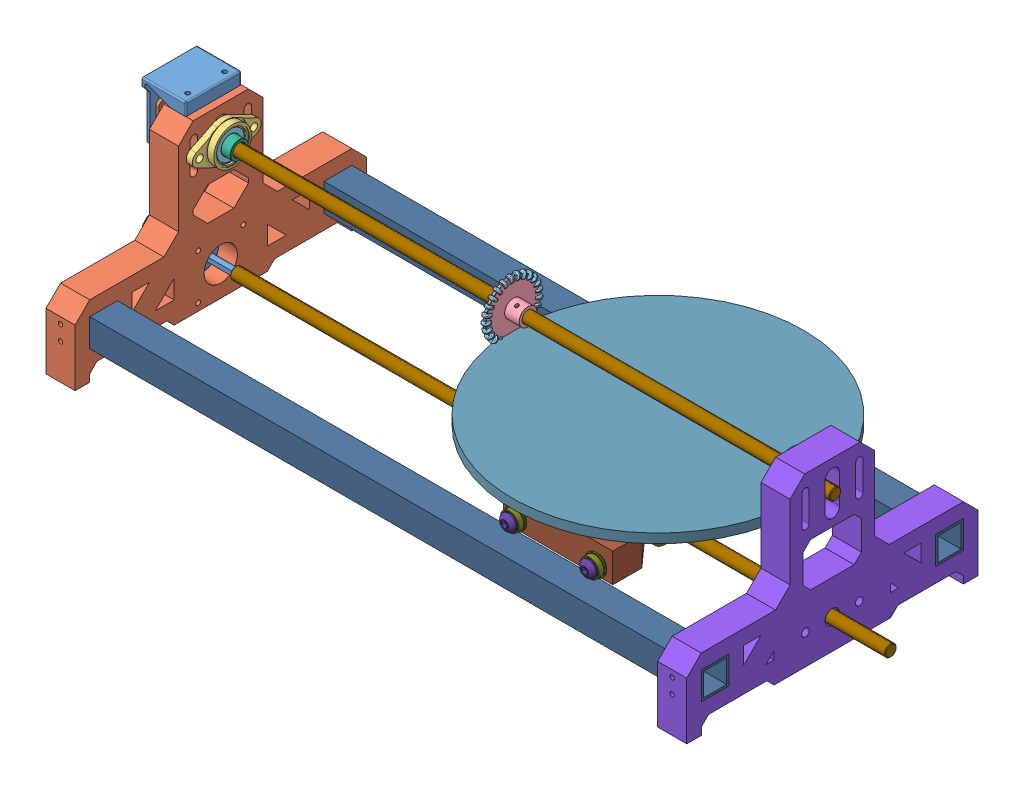
SolidWorks assembly Integrator, configuration Default. Lengths in mm.
Overall size (495.22 128.35 224.42).
89 component instances, 23 part files, 44 mates.
Components (placement in the parent):
- NEMA_17_PHB42S20-410-TB-1: NEMA_17_PHB42S20-410-TB [Default] at (1086 20.8 -85) x (0 -1 0) z (-1 0 0) size (42.3 42.3 43.3)
- Motor Side-1: Motor Side [Default] at (0 0 -100) size (20 120 200)
- Zinc Alloy Pillow Block Flange Bearing KFL08 ID-8mm-1: Zinc Alloy Pillow Block Flange Bearing KFL08 ID-8mm [Default] at (20 99.525 -100) x (0 0 -1) z (1 0 0) size (47.3 26.5 12.88)
  - Zinc Alloy Pillow Block Flange Bearing KFL08 ID-8mm.stp-1: Zinc Alloy Pillow Block Flange Bearing KFL08 ID-8mm.stp [Default] at origin size (47.3 26.5 12.88)
    - Flange.stp-1: Flange.stp [Default] x (-1 0 0) z (0 0 1) size (47.3 26.5 8.16)
    - Bearing 61801-2Z GB_T 276-94.stp-1: Bearing 61801-2Z GB_T 276-94.stp [Default] at (0 0 1.525) x (0 0 1) z (-0.985741 0.16827 0) size (5 21 21)
    - DIN 988 - 13 x 19 x 1.stp-1: DIN 988 - 13 x 19 x 1.stp [Default] at (0 0 5.6917) x (-0.369618 -0.929184 0) z (0 0 1) size (19 19 1)
    - DIN 988 - 13 x 19 x 1.stp-2: DIN 988 - 13 x 19 x 1.stp [Default] at (0 0 1.3583) x (0.999993 0.003767 0) z (0 0 1) size (19 19 1)
    - Collar 8x12.35x11.35.stp-1: Collar 8x12.35x11.35.stp [Default] at (0 0 1.525) x (0.825043 -0.56507 0) z (-0.56507 -0.825043 0) size (12.36 11.35 12.36)
    - IS_ 6094 - M3 x 2(1).stp-1: IS_ 6094 - M3 x 2(1).stp [Default] at (3.7491 -1.3208 9.875) x (0.943181 -0.332278 0) z (0 0 1) size (2 3 3)
    - IS_ 6094 - M3 x 2(1).stp-2: IS_ 6094 - M3 x 2(1).stp [Default] at (-2.2462 -3.2795 9.875) x (-0.56507 -0.825043 0) z (0 0 1) size (2 3 3)
    - IS_ 6094 - M3 x 2(1).stp-3: IS_ 6094 - M3 x 2(1).stp [Default] at (3.7491 -1.3208 9.875) x (0.943181 -0.332278 0) z (0 0 1) size (2 3 3)
- Non-motor Side -1: Non-motor Side  [Default] at (440 0 -100) x (-1 0 0) z (0 0 -1) size (20 120 200)
- Zinc Alloy Pillow Block Flange Bearing KFL08 ID-8mm-2: Zinc Alloy Pillow Block Flange Bearing KFL08 ID-8mm [Default] at (430 25.5 -100) x (0 0 1) z (-1 0 0) size (47.3 26.5 12.88)
  - Zinc Alloy Pillow Block Flange Bearing KFL08 ID-8mm.stp-1: Zinc Alloy Pillow Block Flange Bearing KFL08 ID-8mm.stp [Default] at origin size (47.3 26.5 12.88)
    - Flange.stp-1: Flange.stp [Default] x (-1 0 0) z (0 0 1) size (47.3 26.5 8.16)
    - Bearing 61801-2Z GB_T 276-94.stp-1: Bearing 61801-2Z GB_T 276-94.stp [Default] at (0 0 1.525) x (0 0 1) z (-0.985741 0.16827 0) size (5 21 21)
    - DIN 988 - 13 x 19 x 1.stp-1: DIN 988 - 13 x 19 x 1.stp [Default] at (0 0 5.6917) x (-0.369618 -0.929184 0) z (0 0 1) size (19 19 1)
    - DIN 988 - 13 x 19 x 1.stp-2: DIN 988 - 13 x 19 x 1.stp [Default] at (0 0 1.3583) x (0.999993 0.003767 0) z (0 0 1) size (19 19 1)
    - Collar 8x12.35x11.35.stp-1: Collar 8x12.35x11.35.stp [Default] at (0 0 1.525) x (0.825043 -0.56507 0) z (-0.56507 -0.825043 0) size (12.36 11.35 12.36)
    - IS_ 6094 - M3 x 2(1).stp-1: IS_ 6094 - M3 x 2(1).stp [Default] at (3.7491 -1.3208 9.875) x (0.943181 -0.332278 0) z (0 0 1) size (2 3 3)
    - IS_ 6094 - M3 x 2(1).stp-2: IS_ 6094 - M3 x 2(1).stp [Default] at (-2.2462 -3.2795 9.875) x (-0.56507 -0.825043 0) z (0 0 1) size (2 3 3)
    - IS_ 6094 - M3 x 2(1).stp-3: IS_ 6094 - M3 x 2(1).stp [Default] at (3.7491 -1.3208 9.875) x (0.943181 -0.332278 0) z (0 0 1) size (2 3 3)
- Zinc Alloy Pillow Block Flange Bearing KFL08 ID-8mm-3: Zinc Alloy Pillow Block Flange Bearing KFL08 ID-8mm [Default] at (420 99.525 -100) x (0 0 1) z (-1 0 0) size (47.3 26.5 12.88)
  - Zinc Alloy Pillow Block Flange Bearing KFL08 ID-8mm.stp-1: Zinc Alloy Pillow Block Flange Bearing KFL08 ID-8mm.stp [Default] at origin size (47.3 26.5 12.88)
    - Flange.stp-1: Flange.stp [Default] x (-1 0 0) z (0 0 1) size (47.3 26.5 8.16)
    - Bearing 61801-2Z GB_T 276-94.stp-1: Bearing 61801-2Z GB_T 276-94.stp [Default] at (0 0 1.525) x (0 0 1) z (-0.985741 0.16827 0) size (5 21 21)
    - DIN 988 - 13 x 19 x 1.stp-1: DIN 988 - 13 x 19 x 1.stp [Default] at (0 0 5.6917) x (-0.369618 -0.929184 0) z (0 0 1) size (19 19 1)
    - DIN 988 - 13 x 19 x 1.stp-2: DIN 988 - 13 x 19 x 1.stp [Default] at (0 0 1.3583) x (0.999993 0.003767 0) z (0 0 1) size (19 19 1)
    - Collar 8x12.35x11.35.stp-1: Collar 8x12.35x11.35.stp [Default] at (0 0 1.525) x (0.825043 -0.56507 0) z (-0.56507 -0.825043 0) size (12.36 11.35 12.36)
    - IS_ 6094 - M3 x 2(1).stp-1: IS_ 6094 - M3 x 2(1).stp [Default] at (3.7491 -1.3208 9.875) x (0.943181 -0.332278 0) z (0 0 1) size (2 3 3)
    - IS_ 6094 - M3 x 2(1).stp-2: IS_ 6094 - M3 x 2(1).stp [Default] at (-2.2462 -3.2795 9.875) x (-0.56507 -0.825043 0) z (0 0 1) size (2 3 3)
    - IS_ 6094 - M3 x 2(1).stp-3: IS_ 6094 - M3 x 2(1).stp [Default] at (3.7491 -1.3208 9.875) x (0.943181 -0.332278 0) z (0 0 1) size (2 3 3)
- 8mmby450mm-1: 8mmby450mm [Default] at (-7.888 99.525 -100) x (1 0 0) z (0 -0.729222 0.684277) size (450 8 8)
- .75inby440mm-1: .75inby440mm [Default] at (0 29.525 -180.475) size (440 19.05 19.05)
- .75inby440mm-2: .75inby440mm [Default] at (0 29.525 -19.525) size (440 19.05 19.05)
- 8mmby450mm-2: 8mmby450mm [Default] at (30.3 25.5 -100) x (1 0 0) z (0 0.801211 0.598382) size (450 8 8)
- Cart-1: Cart [Default] at (362.9308 -35.5181 5.9339) x (-1 0 0) z (0 0 -1) size (224.42 72.46 224.42)
  - Cart_base-1: Cart_base [Default] at (5.4308 73.0181 37.6181) size (75 44 139.54)
  - NEMA_17_PHB42S20-410-TB-1: NEMA_17_PHB42S20-410-TB [Default] at (27.9308 1160.0181 151.3181) x (0 0 1) z (0 -1 0) size (42.3 42.3 43.3)
  - Gear-1: Gear [Default] at (42.9308 107.2581 146.6181) x (-0.116014 0 -0.993248) z (0 -1 0) size (44.15 44.15 25.24)
  - Gear - Copy-4: Gear - Copy [Default] at (42.9308 97.2581 106.1181) x (-0.799247 0 0.601003) z (0 1 0) size (44.15 44.15 13.5)
  - Disc-1: Disc [Default] at (42.9308 121.4821 106.1181) x (0.13069 0 0.991423) z (0.991423 0 -0.13069) size (200 6.35 200)
  - socket countersunk head screw_am-1: socket countersunk head screw_am [B18.3.5M - 3 x 0.5 x 30 Socket FCHS  -- 30N] at (58.4308 93.7781 162.1181) x (0 -1 0) z (-0.022228 0 0.999753) size (30 5.35 5.35)
  - socket countersunk head screw_am-2: socket countersunk head screw_am [B18.3.5M - 3 x 0.5 x 30 Socket FCHS  -- 30N] at (58.4308 93.7781 131.1181) x (0 -1 0) z (-0.024735 0 0.999694) size (30 5.35 5.35)
  - socket countersunk head screw_am-3: socket countersunk head screw_am [B18.3.5M - 3 x 0.5 x 30 Socket FCHS  -- 30N] at (27.4308 93.7781 162.1181) x (0 -1 0) z (0.002833 0 0.999996) size (30 5.35 5.35)
  - socket countersunk head screw_am-4: socket countersunk head screw_am [B18.3.5M - 3 x 0.5 x 30 Socket FCHS  -- 30N] at (27.4308 93.7781 131.1181) x (0 -1 0) z (0.022473 0 0.999747) size (30 5.35 5.35)
  - Flanged_0.25x0.5-1: Flanged_0.25x0.5 [Default] at (70.4308 80.8921 36.3481) x (0.805459 0.592651 0) z (-0.592651 0.805459 0) size (14.29 4.76 14.29)
  - Flanged_0.25x0.5-2: Flanged_0.25x0.5 [Default] at (70.4308 80.8921 175.8881) x (0.805459 0.592651 0) z (0.592651 -0.805459 0) size (14.29 4.76 14.29)
  - Flanged_0.25x0.5-3: Flanged_0.25x0.5 [Default] at (15.4308 80.8921 36.3481) x (0.998389 0.056737 0) z (-0.056737 0.998389 0) size (14.29 4.76 14.29)
  - Flanged_0.25x0.5-4: Flanged_0.25x0.5 [Default] at (15.4308 80.8921 175.8881) x (0.998389 0.056737 0) z (0.056737 -0.998389 0) size (14.29 4.76 14.29)
  - Flanged_0.25x0.5-5: Flanged_0.25x0.5 [Default] at (42.9308 96.0516 106.1181) size (14.29 4.76 14.29)
  - Flanged_0.25x0.5-6: Flanged_0.25x0.5 [Default] at (42.9308 108.4646 106.1181) x (-0.194861 0 -0.980831) z (-0.980831 0 0.194861) size (14.29 4.76 14.29)
  - socket button head cap screw_ai-2: socket button head cap screw_ai [SBHCSCREW 0.19-32x0.25-HX-N] at (42.9308 111.03 106.1181) x (0 -1 0) z (0 0 1) size (8.92 9.17 9.17)
  - socket button head cap screw_ai-4: socket button head cap screw_ai [SBHCSCREW 0.25-20x0.25-HX-N] at (70.4308 80.8921 184.0034) x (0 0 -1) z (1 0 0) size (9.7 11.1 11.1)
  - socket button head cap screw_ai-5: socket button head cap screw_ai [SBHCSCREW 0.25-20x0.25-HX-N] at (15.4308 80.8921 184.0034) x (0 0 -1) z (1 0 0) size (9.7 11.1 11.1)
  - socket button head cap screw_ai-6: socket button head cap screw_ai [SBHCSCREW 0.25-20x0.25-HX-N] at (70.4308 80.8921 28.2328) x (0 0 1) z (-1 0 0) size (9.7 11.1 11.1)
  - socket button head cap screw_ai-7: socket button head cap screw_ai [SBHCSCREW 0.25-20x0.25-HX-N] at (15.4308 80.8921 28.2328) x (0 0 1) z (-1 0 0) size (9.7 11.1 11.1)
  - Disc_adapter-1: Disc_adapter [Default] at (42.9308 107.2581 106.1181) size (30.05 10.92 30.05)
- Encoder_mount_VER2-1: Encoder_mount_VER2 [Default] at (-14.92 88.35 -100) x (0 0 -1) z (1 0 0) size (38.1 40 30)
- AS5600 Magntic encoder-1: AS5600 Magntic encoder [Default] at (-12.92 100.7427 -100.0029) x (0 0 -1) z (1 0 0) size (23.2 22.7 2)
- Magnet Holder-1: Magnet Holder [Default] at (-0.92 99.525 -100) x (0 -0.824688 0.565588) z (0 -0.565588 -0.824688) size (12 10 12)
- Follower_wheel-1: Follower_wheel [Default] at (220 99.525 -100) x (1 0 0) z (0 -0.438791 0.898589) size (14.36 42.16 42.24)
  - Follower Wheel-1: Follower Wheel [Default] at origin size (12 37.52 37.56)
  - bead-1: bead [Default] at (0 17.6007 2.2235) x (0 0.125333 -0.992115) z (0.45035 0.885812 0.111904) size (2 5 5)
  - bead-2: bead [Default] at (0 16.4948 6.5307) x (0 0.368125 -0.929776) z (0.45035 0.830153 0.328681) size (2 5 5)
  - bead-3: bead [Default] at (0 14.3524 10.4276) x (0 0.587785 -0.809017) z (0.45035 0.722333 0.524805) size (2 5 5)
  - bead-4: bead [Default] at (0 11.3083 13.6693) x (0 0.770513 -0.637424) z (0.45035 0.569125 0.687954) size (2 5 5)
  - bead-5: bead [Default] at (0 7.5536 16.0521) x (0 0.904827 -0.425779) z (0.45035 0.380158 0.807877) size (2 5 5)
  - bead-6: bead [Default] at (0 3.3243 17.4263) x (0 0.982287 -0.187381) z (0.45035 0.167304 0.877037) size (2 5 5)
  - bead-7: bead [Default] at (0 -1.1139 17.7056) x (0 0.998027 0.062791) z (0.45035 -0.056063 0.89109) size (2 5 5)
  - bead-8: bead [Default] at (0 -5.4821 16.8723) x (0 0.951057 0.309017) z (0.45035 -0.275907 0.849153) size (2 5 5)
  - bead-9: bead [Default] at (0 -9.5059 14.9789) x (0 0.844328 0.535827) z (0.45035 -0.478414 0.75386) size (2 5 5)
  - bead-10: bead [Default] at (0 -12.9323 12.1443) x (0 0.684547 0.728969) z (0.45035 -0.650861 0.611199) size (2 5 5)
  - bead-11: bead [Default] at (0 -15.5462 8.5466) x (0 0.481754 0.876307) z (0.45035 -0.782412 0.430135) size (2 5 5)
  - bead-12: bead [Default] at (0 -17.1832 4.4119) x (0 0.24869 0.968583) z (0.45035 -0.864802 0.222043) size (2 5 5)
  - bead-13: bead [Default] at (0 -17.7406 0) x (0 0 1) z (0.45035 -0.892852 0) size (2 5 5)
  - bead-14: bead [Default] at (0 -17.1832 -4.4119) x (0 -0.24869 0.968583) z (0.45035 -0.864802 -0.222043) size (2 5 5)
  - bead-15: bead [Default] at (0 -15.5462 -8.5466) x (0 -0.481754 0.876307) z (0.45035 -0.782412 -0.430135) size (2 5 5)
  - bead-16: bead [Default] at (0 -12.9323 -12.1443) x (0 -0.684547 0.728969) z (0.45035 -0.650861 -0.611199) size (2 5 5)
  - bead-17: bead [Default] at (0 -9.5059 -14.9789) x (0 -0.844328 0.535827) z (0.45035 -0.478414 -0.75386) size (2 5 5)
  - bead-18: bead [Default] at (0 -5.4821 -16.8723) x (0 -0.951057 0.309017) z (0.45035 -0.275907 -0.849153) size (2 5 5)
  - bead-19: bead [Default] at (0 -1.1139 -17.7056) x (0 -0.998027 0.062791) z (0.45035 -0.056063 -0.89109) size (2 5 5)
  - bead-20: bead [Default] at (0 3.3243 -17.4263) x (0 -0.982287 -0.187381) z (0.45035 0.167304 -0.877037) size (2 5 5)
  - bead-21: bead [Default] at (0 7.5536 -16.0521) x (0 -0.904827 -0.425779) z (0.45035 0.380158 -0.807877) size (2 5 5)
  - bead-22: bead [Default] at (0 11.3083 -13.6693) x (0 -0.770513 -0.637424) z (0.45035 0.569125 -0.687954) size (2 5 5)
  - bead-23: bead [Default] at (0 14.3524 -10.4276) x (0 -0.587785 -0.809017) z (0.45035 0.722333 -0.524805) size (2 5 5)
  - bead-24: bead [Default] at (0 16.4948 -6.5307) x (0 -0.368125 -0.929776) z (0.45035 0.830153 -0.328681) size (2 5 5)
  - bead-25: bead [Default] at (0 17.6007 -2.2235) x (0 -0.125333 -0.992115) z (0.45035 0.885812 -0.111904) size (2 5 5)
Mates (geometry in assembly coordinates):
- Coincident3: coincident anti-aligned: plane of NEMA_17_PHB42S20-410-TB-1 through (6 25.5 -100) normal (1 0 0); plane of Motor Side-1 through (6 0 -100) normal (-1 0 0)
- Concentric3: concentric anti-aligned: cylinder of NEMA_17_PHB42S20-410-TB-1 through (8 25.5 -100) axis (-1 0 0) radius 11; cylinder of Motor Side-1 through (0 25.5 -100) axis (1 0 0) radius 11.5
- Concentric4: concentric anti-aligned: cylinder of NEMA_17_PHB42S20-410-TB-1 through (19 41 -84.5) axis (-1 0 0) radius 1.25; cylinder of Motor Side-1 through (0 41 -84.5) axis (1 0 0) radius 1.6
- Coincident4: coincident anti-aligned: plane of Motor Side-1 through (20 0 -100) normal (1 0 0); plane of Zinc Alloy Pillow Block Flange Bearing KFL08 ID-8mm-1/Zinc Alloy Pillow Block Flange Bearing KFL08 ID-8mm.stp-1/Flange.stp-1 through (20 99.525 -100) normal (-1 0 0)
- Coincident12: coincident aligned: plane of Motor Side-1 through (20 0 -100) normal (0 -1 0); plane of Non-motor Side -1 through (420 0 -100) normal (0 -1 0)
- Distance3: distance = 400 mm anti-aligned: plane of Non-motor Side -1 through (420 0 -100) normal (-1 0 0); plane of Motor Side-1 through (20 0 -100) normal (1 0 0)
- Concentric7: concentric anti-aligned: cylinder of Motor Side-1 through (0 25.5 -100) axis (1 0 0) radius 11.5; cylinder of Non-motor Side -1 through (440 25.5 -100) axis (-1 0 0) radius 5
- Coincident17: coincident anti-aligned: plane of Non-motor Side -1 through (430 0 -100) normal (-1 0 0); plane of Zinc Alloy Pillow Block Flange Bearing KFL08 ID-8mm-2/Zinc Alloy Pillow Block Flange Bearing KFL08 ID-8mm.stp-1/Flange.stp-1 through (430 25.5 -100) normal (1 0 0)
- Concentric8: concentric aligned: cylinder of Non-motor Side -1 through (440 25.5 -100) axis (-1 0 0) radius 5; cylinder of Zinc Alloy Pillow Block Flange Bearing KFL08 ID-8mm-2/Zinc Alloy Pillow Block Flange Bearing KFL08 ID-8mm.stp-1/Collar 8x12.35x11.35.stp-1 through (428.475 25.5 -100) axis (-1 0 0) radius 4
- Coincident19: coincident anti-aligned: plane of Non-motor Side -1 through (420 0 -100) normal (-1 0 0); plane of Zinc Alloy Pillow Block Flange Bearing KFL08 ID-8mm-3/Zinc Alloy Pillow Block Flange Bearing KFL08 ID-8mm.stp-1/Flange.stp-1 through (420 99.525 -100) normal (1 0 0)
- Width1: width: plane of Non-motor Side -1 through (440 109.05 -105) normal (0 0 1); plane of Non-motor Side -1 through (440 109.05 -95) normal (0 0 -1); cylinder of Zinc Alloy Pillow Block Flange Bearing KFL08 ID-8mm-3/Zinc Alloy Pillow Block Flange Bearing KFL08 ID-8mm.stp-1/Collar 8x12.35x11.35.stp-1 through (418.475 99.525 -100) axis (-1 0 0) radius 4
- Concentric12: concentric anti-aligned: cylinder of Zinc Alloy Pillow Block Flange Bearing KFL08 ID-8mm-1/Zinc Alloy Pillow Block Flange Bearing KFL08 ID-8mm.stp-1/Flange.stp-1 through (20 99.525 -118.65) axis (1 0 0) radius 2.5; cylinder of Zinc Alloy Pillow Block Flange Bearing KFL08 ID-8mm-3/Zinc Alloy Pillow Block Flange Bearing KFL08 ID-8mm.stp-1/Flange.stp-1 through (420 99.525 -118.65) axis (-1 0 0) radius 2.5
- Width2: width: plane of Motor Side-1 through (20 109.05 -105) normal (0 0 1); plane of Motor Side-1 through (20 109.05 -95) normal (0 0 -1); cylinder of Zinc Alloy Pillow Block Flange Bearing KFL08 ID-8mm-1/Zinc Alloy Pillow Block Flange Bearing KFL08 ID-8mm.stp-1/Collar 8x12.35x11.35.stp-1 through (21.525 99.525 -100) axis (1 0 0) radius 4
- Width3: width aligned: plane of Motor Side-1 through (20 109.05 -105) normal (0 0 1); plane of Motor Side-1 through (20 109.05 -95) normal (0 0 -1); plane of Zinc Alloy Pillow Block Flange Bearing KFL08 ID-8mm-1/Zinc Alloy Pillow Block Flange Bearing KFL08 ID-8mm.stp-1/Flange.stp-1 through (20 104.0092 -120.8618) normal (0 0.896838 -0.442359); plane of Zinc Alloy Pillow Block Flange Bearing KFL08 ID-8mm-1/Zinc Alloy Pillow Block Flange Bearing KFL08 ID-8mm.stp-1/Flange.stp-1 through (20 111.4081 -94.1387) normal (0 0.896838 0.442359)
- Concentric14: concentric anti-aligned: cylinder of Zinc Alloy Pillow Block Flange Bearing KFL08 ID-8mm-1/Zinc Alloy Pillow Block Flange Bearing KFL08 ID-8mm.stp-1/Collar 8x12.35x11.35.stp-1 through (21.525 99.525 -100) axis (1 0 0) radius 4; cylinder of 8mmby450mm-1 through (442.112 99.525 -100) axis (-1 0 0) radius 4
- Width4: width: plane of Non-motor Side -1 through (430 40.5 -70) normal (0 -1 0); plane of Non-motor Side -1 through (430 10.5 -70) normal (0 1 0); cylinder of Zinc Alloy Pillow Block Flange Bearing KFL08 ID-8mm-2/Zinc Alloy Pillow Block Flange Bearing KFL08 ID-8mm.stp-1/Flange.stp-1 through (430 25.5 -81.35) axis (-1 0 0) radius 2.5
- Coincident27: coincident anti-aligned: plane of Motor Side-1 through (0 39.05 -190) normal (0 -1 0); plane of .75inby440mm-1 through (440 39.05 -190) normal (0 1 0)
- Coincident28: coincident anti-aligned: plane of Motor Side-1 through (0 39.05 -190) normal (0 0 1); plane of .75inby440mm-1 through (440 39.05 -190) normal (0 0 -1)
- Coincident29: coincident aligned: plane of Non-motor Side -1 through (440 0 -100) normal (1 0 0); plane of .75inby440mm-1 through (440 29.525 -180.475) normal (1 0 0)
- Coincident30: coincident aligned: plane of Non-motor Side -1 through (440 0 -100) normal (1 0 0); plane of .75inby440mm-2 through (440 29.525 -19.525) normal (1 0 0)
- Coincident31: coincident anti-aligned: plane of Non-motor Side -1 through (440 39.05 -10) normal (0 -1 0); plane of .75inby440mm-2 through (440 39.05 -29.05) normal (0 1 0)
- Coincident32: coincident anti-aligned: plane of Non-motor Side -1 through (440 39.05 -10) normal (0 0 -1); plane of .75inby440mm-2 through (440 39.05 -10) normal (0 0 1)
- Coincident33: coincident anti-aligned: plane of NEMA_17_PHB42S20-410-TB-1 through (30.3 25.5 -100) normal (1 0 0); plane of 8mmby450mm-2 through (30.3 25.5 -100) normal (-1 0 0)
- Width6: width: plane of Non-motor Side -1 through (420 120 -100) normal (0 1 0); plane of Non-motor Side -1 through (440 79.05 -120) normal (0 -1 0); cylinder of Zinc Alloy Pillow Block Flange Bearing KFL08 ID-8mm-3/Zinc Alloy Pillow Block Flange Bearing KFL08 ID-8mm.stp-1/Collar 8x12.35x11.35.stp-1 through (418.475 99.525 -100) axis (-1 0 0) radius 6.175
- Parallel7: parallel aligned: plane of .75inby440mm-1 through (440 39.05 -190) normal (0 1 0); plane of Cart-1/Cart_base-1 through (282.5 57.5 -31.6842) normal (0 1 0)
- Concentric15: concentric anti-aligned: cylinder of NEMA_17_PHB42S20-410-TB-1 through (8 25.5 -100) axis (1 0 0) radius 2.5; cylinder of 8mmby450mm-2 through (480.3 25.5 -100) axis (-1 0 0) radius 4
- Concentric19: concentric anti-aligned: cylinder of 8mmby450mm-2 through (480.3 25.5 -100) axis (-1 0 0) radius 4; cylinder of Cart-1/Cart_base-1 through (282.5 25.5 -100) axis (1 0 0) radius 5.25
- Coincident35: coincident: plane of Motor Side-1 through (20 120 -100) normal (0 1 0); plane of Encoder_mount-1 through (14.2758 120 -119.05) normal (0 -1 0)
- Width7: width anti-aligned: plane of Motor Side-1 through (0 120 -129) normal (0 0 -1); plane of Encoder_mount_VER2-1 through (0 120 -71) normal (0 0 1); plane of Motor Side-1 through (-14.92 88.35 -80.95) normal (0 0 1); plane of Encoder_mount_VER2-1 through (-14.92 88.35 -119.05) normal (0 0 -1)
- Coincident36: coincident anti-aligned: plane of Encoder_mount-1 through (-12.92 88.35 -119.05) normal (1 0 0); plane of AS5600 Magntic encoder-1 through (-12.92 100.7427 -100.0029) normal (-1 0 0)
- Width8: width anti-aligned: plane of Encoder_mount_VER2-1 through (-14.92 88.35 -115.7864) normal (0 0 -1); plane of AS5600 Magntic encoder-1 through (-14.92 88.35 -84.2136) normal (0 0 1); plane of Encoder_mount_VER2-1 through (-10.92 111.8456 -88.4) normal (0 0 1); plane of AS5600 Magntic encoder-1 through (-10.92 111.8456 -111.6) normal (0 0 -1)
- Concentric24: concentric anti-aligned: cylinder of 8mmby450mm-1 through (442.112 99.525 -100) axis (-1 0 0) radius 4; cylinder of Magnet Holder-1 through (-20.3431 99.525 -100) axis (1 0 0) radius 4.05
- Coincident37: coincident anti-aligned: plane of 8mmby450mm-1 through (-7.888 99.525 -100) normal (-1 0 0); plane of Magnet Holder-1 through (-7.888 99.525 -100) normal (1 0 0)
- Coincident38: coincident anti-aligned: plane of AS5600 Magntic encoder-1 through (-10.92 100.7427 -100.0029) normal (1 0 0); plane of Magnet Holder-1 through (-10.92 99.525 -100) normal (-1 0 0)
- Coincident39: coincident anti-aligned: plane of Motor Side-1 through (20 0 -100) normal (0 -1 0)
- Coincident40: coincident aligned: plane of Motor Side-1 through (20 0 0) normal (0 0 1)
- Coincident41: coincident anti-aligned: plane of Motor Side-1 through (0 0 -100) normal (-1 0 0)
- Concentric25: concentric aligned: cylinder of 8mmby450mm-1 through (442.112 99.525 -100) axis (-1 0 0) radius 4; cylinder of Follower_wheel-1/Follower Wheel-1 through (221 99.525 -100) axis (-1 0 0) radius 4.05
- Width9: width anti-aligned: plane of Non-motor Side -1 through (420 0 -100) normal (-1 0 0); plane of Motor Side-1 through (20 0 -100) normal (1 0 0); plane of Follower_wheel-1/Follower Wheel-1 through (221 99.525 -100) normal (1 0 0); plane of Follower_wheel-1/Follower Wheel-1 through (219 99.525 -100) normal (-1 0 0)
- Slot1: slot anti-aligned: plane of ? through (-14.92 95.0515 -106.525) normal (0 0 -1); cylinder of ? through (-10.92 115.471 -108.025) axis (-1 0 0) radius 1.6; cylinder of ? through (-14.92 115.471 -108.025) axis (1 0 0) radius 1.5
- Slot2: slot: plane of ? through (10 102.95 -111.15) normal (0 0 -1); cylinder of Motor Side-1 through (10 110 -112.7) axis (0 1 0) radius 1.45; cylinder of ? through (10 102.95 -112.7) axis (0 1 0) radius 1.55
- Width10: width: plane of Motor Side-1 through (20 0 -100) normal (1 0 0); plane of Non-motor Side -1 through (420 0 -100) normal (-1 0 0); cylinder of Cart-1/Disc-1 through (320 79.614 -100.1842) axis (0 1 0) radius 100
- Concentric26: concentric aligned: cylinder of Motor Side-1 through (10 110 -112.7) axis (0 1 0) radius 1.45; cylinder of Encoder_mount_VER2-1 through (10 115.7574 -112.7) axis (0 1 0) radius 1.5
- Coincident42: coincident anti-aligned: plane of Motor Side-1 through (20 120 -100) normal (0 1 0); plane of Encoder_mount_VER2-1 through (4.92 120 -52.239) normal (0 -1 0)
